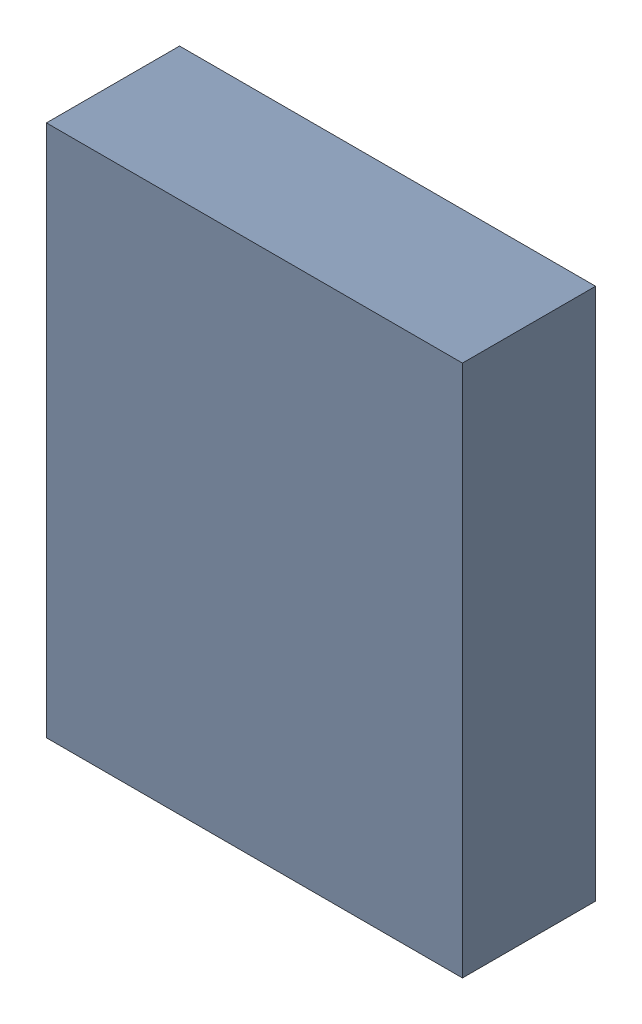
SolidWorks assembly X3, configuration Standard. Lengths in mm.
Overall size (2.5 3.2 0.8).
2 component instances, 1 part files, 0 mates.
Components (placement in the parent):
- 885544824-1: 885544824 [Standard] at (15.2 -15.95 0) size (2.5 3.2 0.8)
  - Extruded_8-1: Extruded_8 [Standard] at origin size (2.5 3.2 0.8)
